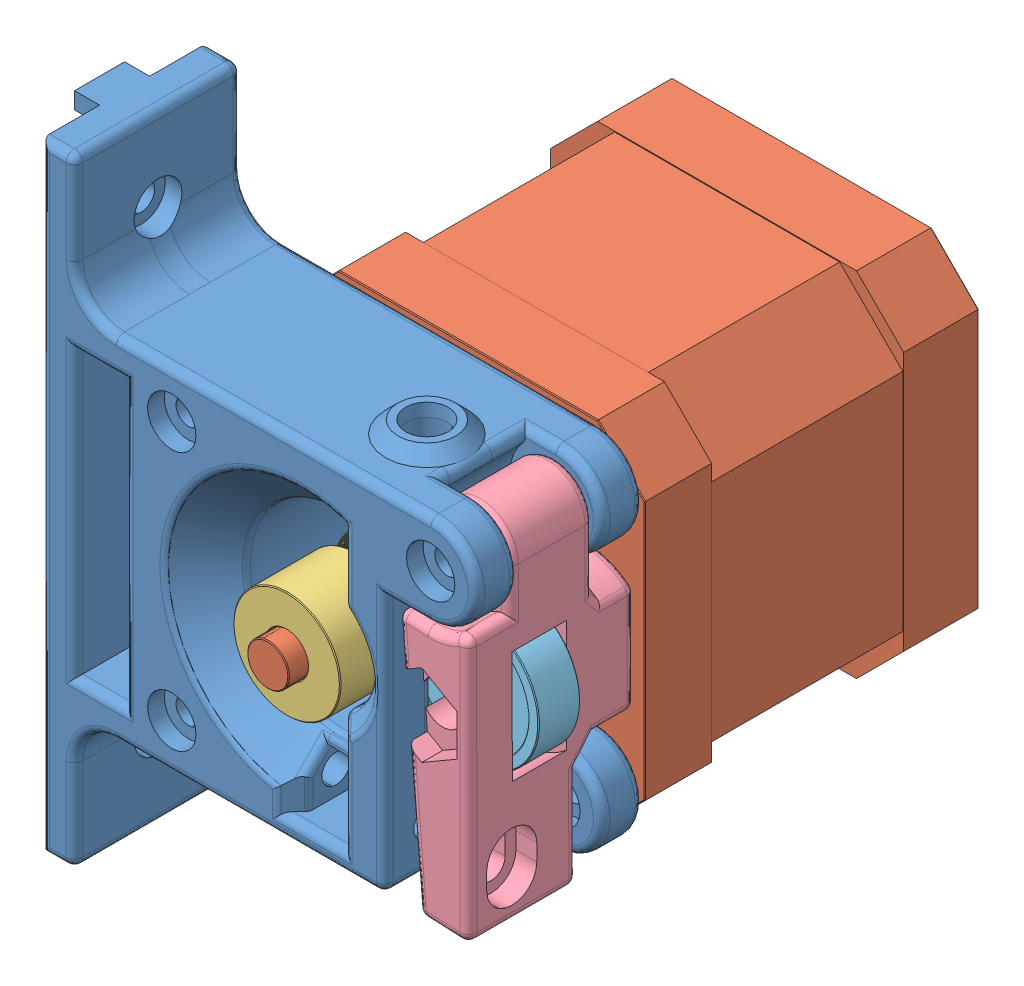
SolidWorks assembly assembled_extruder_dd, configuration Default. Lengths in mm.
Overall size (58.17 74 64).
5 component instances, 5 part files, 10 mates.
Components (placement in the parent):
- extruder_dd_body-1: extruder_dd_body [Default] at origin size (55.15 74 20.1)
- nema_17_steppermotor-1: nema_17_steppermotor [Default] at (0 0 -40) x (1 0 0) z (0 -1 0) size (42.3 64 42.3)
- metal gear-1: metal gear [Default] at (0 0 13.5414) x (0.860665 -0.509171 0) z (0 0 1) size (12.82 12.82 13.12)
- extruder_dd_hinge-1: extruder_dd_hinge [Default] at (-0.7261 0.7619 5) x (0.998847 -0.048001 0) z (0 0 1) size (10.76 41 20.07)
- bearing_16x5-1: bearing_16x5 [Default] at (14.4314 0.0335 11.5) x (0.974486 0.224448 0) z (0 0 1) size (16 16 5)
Mates (geometry in assembly coordinates):
- Coincident1: coincident anti-aligned: plane of extruder_dd_body-1 through (0 0 0) normal (0 0 -1); plane of nema_17_steppermotor-1 through (0 0 0) normal (0 0 1)
- Concentric1: concentric aligned: cylinder of extruder_dd_body-1 through (-15.5 -15.5 5) axis (0 0 -1) radius 1.5; cylinder of nema_17_steppermotor-1 through (-15.5 -15.5 -31) axis (0 0 -1) radius 1.5
- Concentric2: concentric aligned: cylinder of extruder_dd_body-1 through (15.5 15.5 5) axis (0 0 -1) radius 1.5; cylinder of nema_17_steppermotor-1 through (15.5 15.5 -31) axis (0 0 -1) radius 1.5
- Concentric3: concentric aligned: cylinder of nema_17_steppermotor-1 through (0 0 53.0711) axis (0 0 -1) radius 2.5; cylinder of metal gear-1 through (0 0 13.5414) axis (0 0 -1) radius 2.52
- Coincident2: coincident anti-aligned: plane of extruder_dd_body-1 through (0 0 5) normal (0 0 1); plane of extruder_dd_hinge-1 through (15.5 15.5 5) normal (0 0 -1)
- Coincident3: coincident anti-aligned: plane of extruder_dd_body-1 through (15.5 15.5 15) normal (0 0 -1); plane of extruder_dd_hinge-1 through (15.5 15.5 15) normal (0 0 1)
- Concentric4: concentric aligned: cylinder of extruder_dd_body-1 through (15.5 15.5 18) axis (0 0 -1) radius 1.5; cylinder of extruder_dd_hinge-1 through (15.5 15.5 51.1501) axis (0 0 -1) radius 1.5
- Coincident4: coincident anti-aligned: plane of extruder_dd_hinge-1 through (14.4314 0.0335 14) normal (0 0 -1); plane of bearing_16x5-1 through (14.4314 0.0335 14) normal (0 0 1)
- Coincident5: coincident anti-aligned: plane of extruder_dd_hinge-1 through (14.4314 0.0335 9) normal (0 0 1); plane of bearing_16x5-1 through (14.4314 0.0335 9) normal (0 0 -1)
- Concentric5: concentric anti-aligned: cylinder of extruder_dd_hinge-1 through (14.4314 0.0335 51.1501) axis (0 0 -1) radius 2.5; cylinder of bearing_16x5-1 through (14.4314 0.0335 9) axis (0 0 1) radius 2.5
